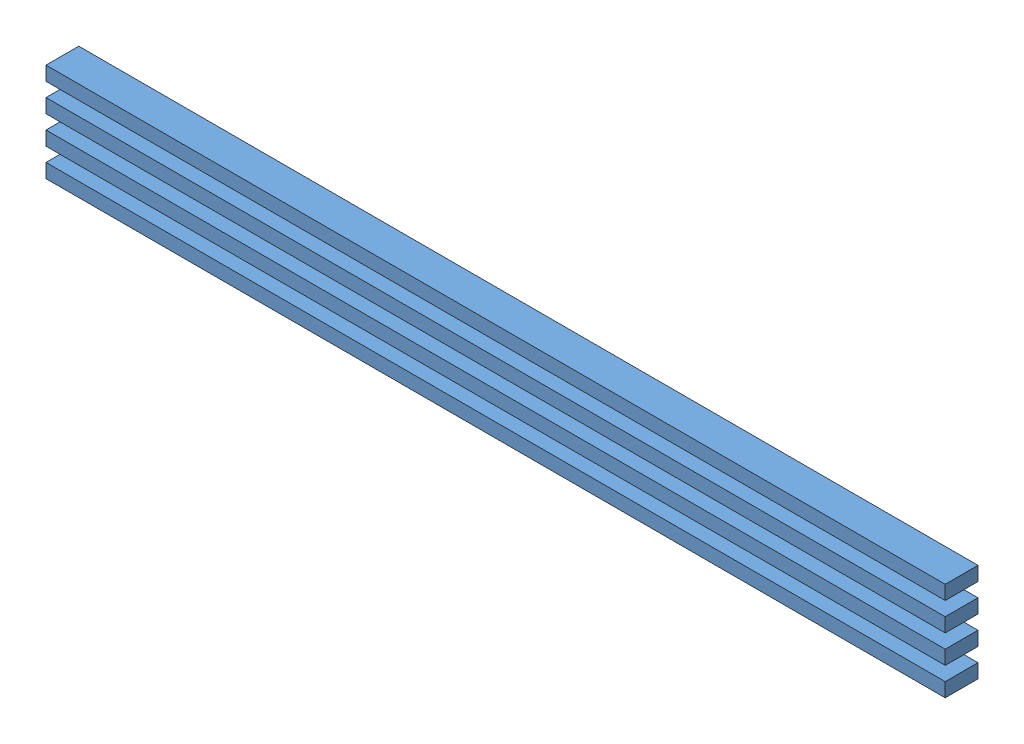
SolidWorks assembly truss_beam, configuration Default. Lengths in mm.
Overall size (2438.4 266.7 88.9).
4 component instances, 1 part files, 0 mates.
Components (placement in the parent):
- 2x4-1: 2x4 [Default] at (-564.0137 1340.2575 1902.8101) size (2438.4 38.1 88.9)
- 2x4-2: 2x4 [Default] at (-564.0137 1416.4575 1902.8101) size (2438.4 38.1 88.9)
- 2x4-3: 2x4 [Default] at (-564.0137 1492.6575 1902.8101) size (2438.4 38.1 88.9)
- 2x4-4: 2x4 [Default] at (-564.0137 1568.8575 1902.8101) size (2438.4 38.1 88.9)
